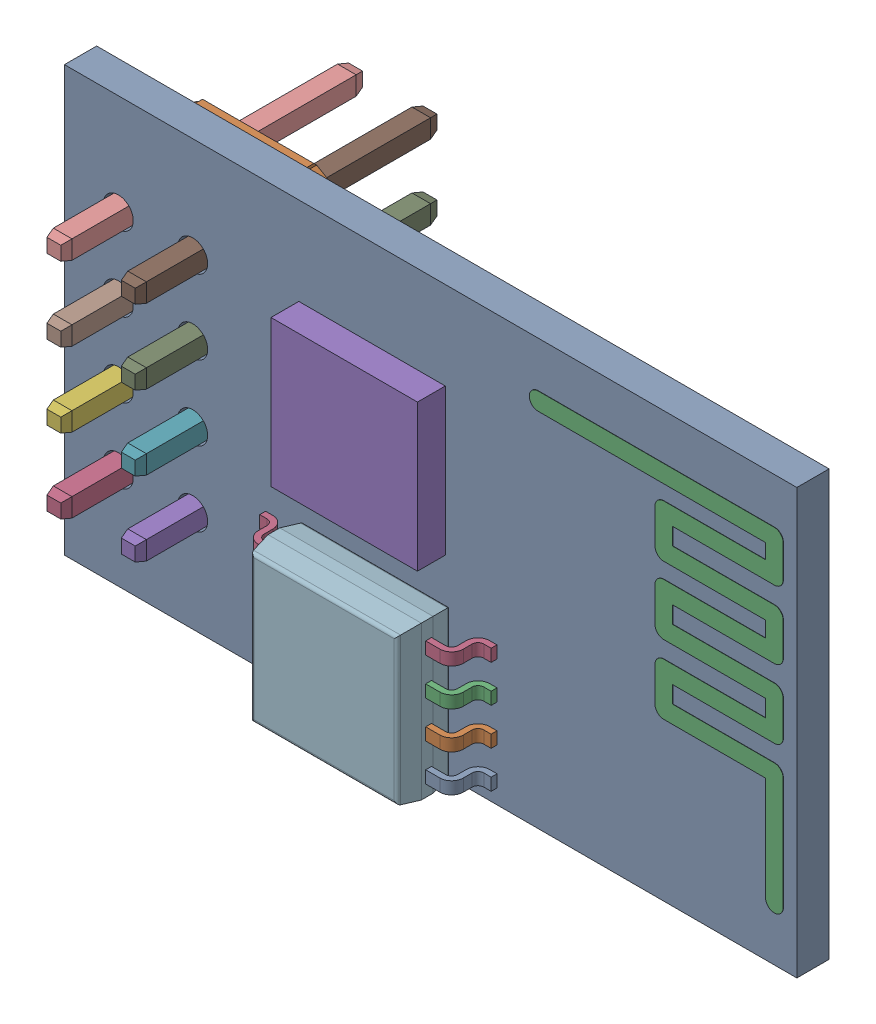
SolidWorks assembly ESP01 v1(2), configuration Valor predeterminado. Lengths in mm.
Overall size (25 14.5 10.3).
13 component instances, 6 part files, 0 mates.
Components (placement in the parent):
- Platine-1: Platine [Valor predeterminado] at origin size (25 14.5 1.1)
- PinSockel-1: PinSockel [Valor predeterminado] at (1.8391 11.06 0) x (1 0 0) z (0 0 -1) size (5 10.16 2.5)
- PCB_Antenna-1: PCB_Antenna [Valor predeterminado] at (1 16 0.81) x (0 -1 0) z (-1 0 0) size (11.4 0.04 8.66)
- Pin_Stiftleiste-1: Pin_Stiftleiste [Valor predeterminado] at (1.8391 3.44 0) x (-1 0 0) z (0 0 -1) size (0.64 0.64 10.3)
- Pin_Stiftleiste-2: Pin_Stiftleiste [Valor predeterminado] at (4.3791 3.44 0) x (-1 0 0) z (0 0 -1) size (0.64 0.64 10.3)
- Pin_Stiftleiste-3: Pin_Stiftleiste [Valor predeterminado] at (1.8391 5.98 0) x (-1 0 0) z (0 0 -1) size (0.64 0.64 10.3)
- Pin_Stiftleiste-4: Pin_Stiftleiste [Valor predeterminado] at (4.3791 5.98 0) x (-1 0 0) z (0 0 -1) size (0.64 0.64 10.3)
- Pin_Stiftleiste-5: Pin_Stiftleiste [Valor predeterminado] at (1.8391 8.52 0) x (-1 0 0) z (0 0 -1) size (0.64 0.64 10.3)
- Pin_Stiftleiste-6: Pin_Stiftleiste [Valor predeterminado] at (4.3791 8.52 0) x (-1 0 0) z (0 0 -1) size (0.64 0.64 10.3)
- Pin_Stiftleiste-7: Pin_Stiftleiste [Valor predeterminado] at (1.8391 11.06 0) x (-1 0 0) z (0 0 -1) size (0.64 0.64 10.3)
- Pin_Stiftleiste-8: Pin_Stiftleiste [Valor predeterminado] at (4.3791 11.06 0) x (-1 0 0) z (0 0 -1) size (0.64 0.64 10.3)
- SerialFlashMem-1: SerialFlashMem [Valor predeterminado] at (8.2 0.1 1.1) size (7.9 5.23 1.95)
- ESP8266EX-1: ESP8266EX [Valor predeterminado] at (8 6.5 1.1) size (5 5 0.95)
